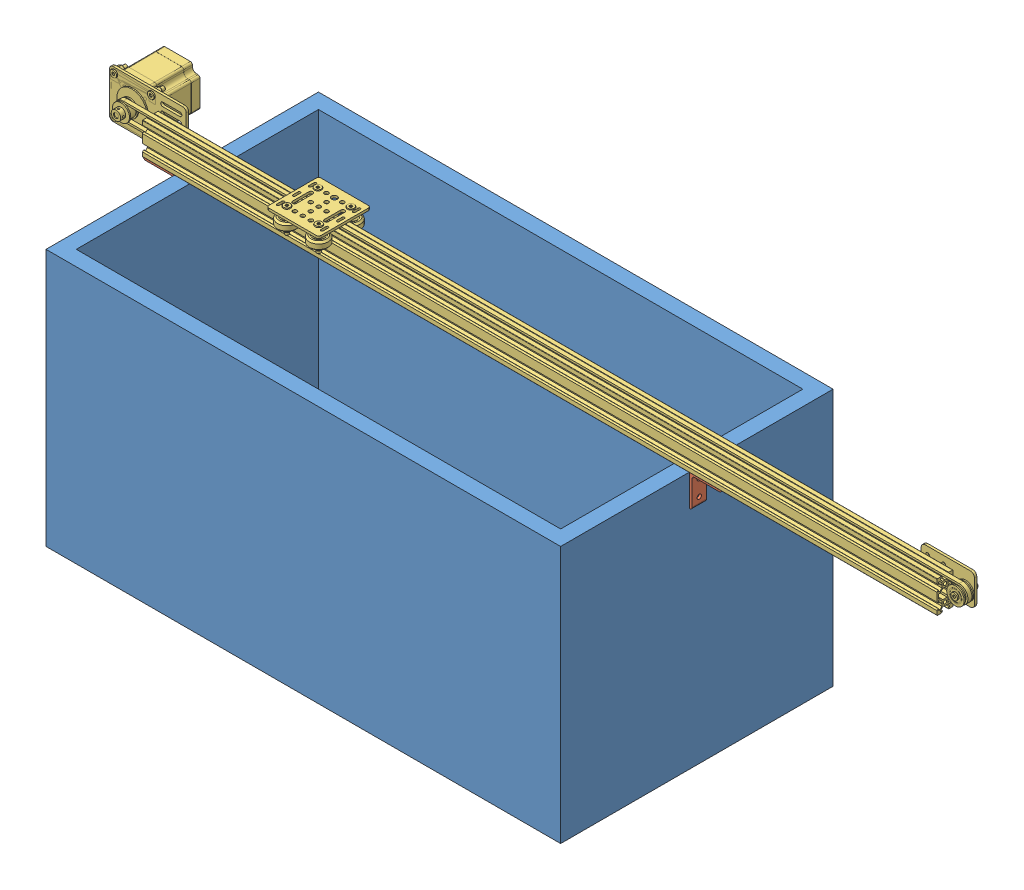
SolidWorks assembly Full_Assembly, configuration Default. Lengths in mm.
Overall size (1092.65 383.85 342.9).
13 component instances, 5 part files, 25 mates.
Components (placement in the parent):
- ST_TestBox-1: ST_TestBox [Default] at (295.9111 425.7121 283.3654) size (727.7 323.85 342.9)
  - ST_WoodenBox-1: ST_WoodenBox [Default] at origin size (647.7 323.85 342.9)
  - MT_CornerBracket_Extended-1: MT_CornerBracket_Extended [5537T441] at (323.85 323.85 0) x (1 0 0) z (0 0 -1) size (40 40 18)
  - MT_CornerBracket_Extended-2: MT_CornerBracket_Extended [5537T441] at (-323.85 323.85 0) x (-1 0 0) z (0 0 1) size (40 40 18)
- Prebuilt_Linear_Rail-1: Prebuilt_Linear_Rail [Default] at (432.0611 779.5621 263.3654) x (0 -1 0) z (0 0 1) size (64.5 1092.65 98.62)
- MT_T-slot_nut-1: MT_T-slot_nut [5537T651] at (-57.9389 752.2621 283.3654) x (-1 0 0) z (0 1 0) size (15 8 3.62)
- MT_T-slot_bolt-1: MT_T-slot_bolt [91290A222] at (-57.9389 748.0621 283.3654) x (1 0 0) z (0 -1 0) size (8.5 8.5 13.3)
- MT_T-slot_bolt-2: MT_T-slot_bolt [91290A222] at (-37.9389 748.0621 283.3654) x (0.973543 0 0.228502) z (0 -1 0) size (8.5 8.5 13.3)
- MT_T-slot_nut-2: MT_T-slot_nut [5537T651] at (-37.9389 752.2621 283.3654) x (-1 0 0) z (0 1 0) size (15 8 3.62)
- MT_T-slot_bolt-3: MT_T-slot_bolt [91290A222] at (629.7611 748.0621 283.3654) x (0.918365 0 -0.395734) z (0 -1 0) size (8.5 8.5 13.3)
- MT_T-slot_nut-3: MT_T-slot_nut [5537T651] at (629.7611 752.2621 283.3654) x (-1 0 0) z (0 1 0) size (15 8 3.62)
- MT_T-slot_bolt-4: MT_T-slot_bolt [91290A222] at (649.7611 748.0621 283.3654) x (0.8 0 -0.6) z (0 -1 0) size (8.5 8.5 13.3)
- MT_T-slot_nut-4: MT_T-slot_nut [5537T651] at (649.7611 752.2621 283.3654) x (-1 0 0) z (0 1 0) size (15 8 3.62)
Mates (geometry in assembly coordinates):
- Coincident1: coincident anti-aligned: plane of ST_TestBox-1/ST_WoodenBox-1 through (295.9111 749.5621 283.3654) normal (0 1 0); plane of Prebuilt_Linear_Rail-1 through (-67.9389 749.5621 292.8654) normal (0 -1 0)
- Coincident2: coincident: plane of ST_TestBox-1/MT_LongCornerBracket-2 through (285.6808 882.9121 131.5246) normal (0 0 -1); plane of Prebuilt_Linear_Rail-1 through (566.4191 779.5621 283.3654) normal (0 0 1)
- Coincident3: coincident: line of ST_TestBox-1/MT_LongCornerBracket-2 through (234.8808 882.9121 120.4121) axis (0 0 1); plane of Prebuilt_Linear_Rail-1 through (66.4191 750.0621 292.8654) normal (-1 0 0)
- Coincident4: coincident anti-aligned: plane of Prebuilt_Linear_Rail-1 through (-67.9389 751.3621 277.8654) normal (0 1 0); plane of MT_T-slot_nut-1 through (-50.0107 751.3621 287.3654) normal (0 -1 0)
- Coincident6: coincident aligned: plane of Prebuilt_Linear_Rail-1 through (432.0611 779.5621 283.3654) normal (0 0 1); plane of MT_T-slot_nut-1 through (-57.9389 752.2621 283.3654) normal (0 0 1)
- Coincident7: coincident anti-aligned: plane of ST_TestBox-1/MT_CornerBracket_Extended-2 through (-33.9389 746.5621 292.3654) normal (0 -1 0); plane of MT_T-slot_bolt-1 through (-61.9389 746.5621 283.3654) normal (0 1 0)
- Concentric1: concentric aligned: cylinder of ST_TestBox-1/MT_CornerBracket_Extended-2 through (-57.9389 709.5621 283.3654) axis (0 1 0) radius 2.75; circle of MT_T-slot_bolt-1
- Concentric2: concentric anti-aligned: cylinder of MT_T-slot_nut-1 through (-57.9389 754.3621 283.3654) axis (0 -1 0) radius 3; circle of MT_T-slot_bolt-1
- Coincident9: coincident aligned: plane of ST_TestBox-1 through (295.9111 425.7121 283.3654) normal (0 0 1); plane of Prebuilt_Linear_Rail-1 through (432.0611 779.5621 283.3654) normal (0 0 1)
- Concentric3: concentric anti-aligned: circle of MT_T-slot_bolt-2; cylinder of MT_T-slot_nut-2 through (-37.9389 754.3621 283.3654) axis (0 -1 0) radius 3
- Concentric4: concentric anti-aligned: circle of ST_TestBox-1/MT_CornerBracket_Extended-2; circle of MT_T-slot_bolt-2
- Coincident13: coincident anti-aligned: plane of Prebuilt_Linear_Rail-1 through (-67.9389 751.3621 277.8654) normal (0 1 0); plane of MT_T-slot_nut-2 through (-30.0107 751.3621 287.3654) normal (0 -1 0)
- Coincident14: coincident aligned: plane of Prebuilt_Linear_Rail-1 through (432.0611 779.5621 283.3654) normal (0 0 1); plane of MT_T-slot_nut-2 through (-37.9389 752.2621 283.3654) normal (0 0 1)
- Coincident16: coincident anti-aligned: plane of ST_TestBox-1/MT_CornerBracket_Extended-2 through (-33.9389 746.5621 292.3654) normal (0 -1 0); plane of MT_T-slot_bolt-2 through (-41.8331 746.5621 282.4514) normal (0 1 0)
- Concentric5: concentric anti-aligned: circle of MT_T-slot_bolt-3; cylinder of MT_T-slot_nut-3 through (629.7611 754.3621 283.3654) axis (0 -1 0) radius 3
- Coincident17: coincident anti-aligned: plane of Prebuilt_Linear_Rail-1 through (-67.9389 751.3621 277.8654) normal (0 1 0); plane of MT_T-slot_nut-3 through (637.6893 751.3621 287.3654) normal (0 -1 0)
- Coincident18: coincident aligned: plane of Prebuilt_Linear_Rail-1 through (432.0611 779.5621 283.3654) normal (0 0 1); plane of MT_T-slot_nut-3 through (629.7611 752.2621 283.3654) normal (0 0 1)
- Coincident19: coincident anti-aligned: plane of ST_TestBox-1/MT_CornerBracket_Extended-2 through (-33.9389 746.5621 292.3654) normal (0 -1 0); plane of MT_T-slot_bolt-3 through (626.0876 746.5621 284.9483) normal (0 1 0)
- Concentric6: concentric aligned: cylinder of ST_TestBox-1/MT_CornerBracket_Extended-1 through (629.7611 709.5621 283.3654) axis (0 1 0) radius 2.75; circle of MT_T-slot_bolt-3
- Concentric7: concentric anti-aligned: circle of MT_T-slot_bolt-4; cylinder of MT_T-slot_nut-4 through (649.7611 754.3621 283.3654) axis (0 -1 0) radius 3
- Coincident20: coincident anti-aligned: plane of Prebuilt_Linear_Rail-1 through (-67.9389 751.3621 277.8654) normal (0 1 0); plane of MT_T-slot_nut-4 through (657.6893 751.3621 287.3654) normal (0 -1 0)
- Coincident21: coincident aligned: plane of Prebuilt_Linear_Rail-1 through (432.0611 779.5621 283.3654) normal (0 0 1); plane of MT_T-slot_nut-4 through (649.7611 752.2621 283.3654) normal (0 0 1)
- Coincident22: coincident anti-aligned: plane of ST_TestBox-1/MT_CornerBracket_Extended-2 through (-33.9389 746.5621 292.3654) normal (0 -1 0); plane of MT_T-slot_bolt-4 through (646.5611 746.5621 285.7654) normal (0 1 0)
- Concentric8: concentric aligned: cylinder of ST_TestBox-1/MT_CornerBracket_Extended-1 through (649.7611 709.5621 283.3654) axis (0 1 0) radius 2.75; circle of MT_T-slot_bolt-4
- Coincident26: coincident: line of ST_TestBox-1/MT_CornerBracket_Extended-2 through (-67.9389 749.5621 292.3654) axis (0 0 -1); plane of Prebuilt_Linear_Rail-1 through (-67.9389 750.0621 292.8654) normal (-1 0 0)
